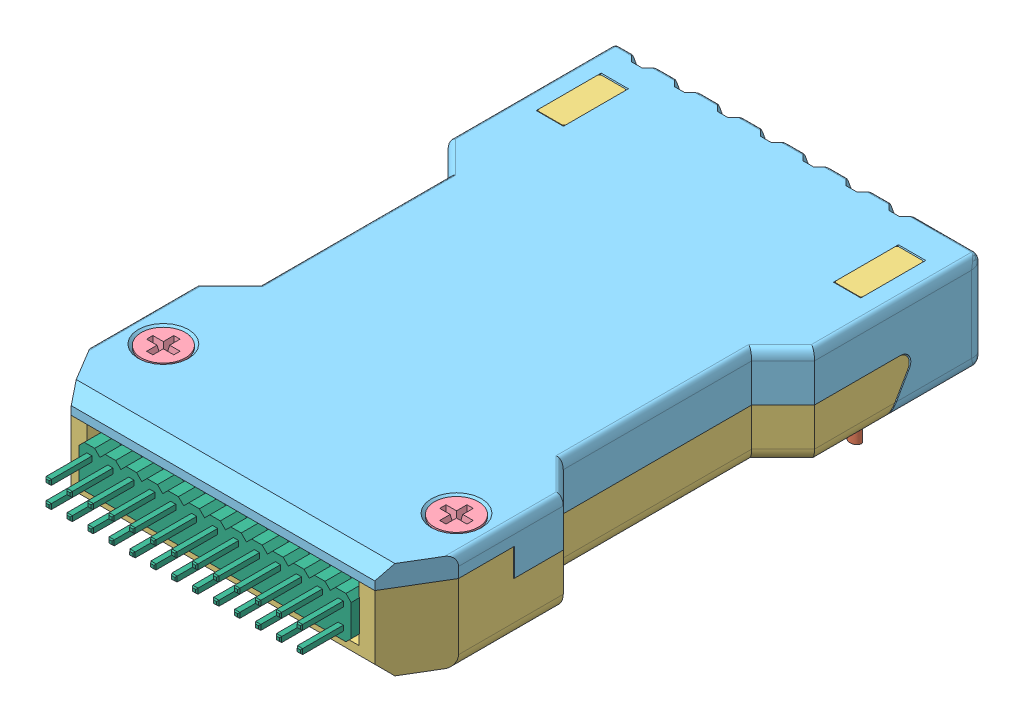
SolidWorks assembly connector2, configuration Default. Lengths in mm.
Overall size (35.01 15.03 59.91).
7 component instances, 6 part files, 16 mates.
Components (placement in the parent):
- board^connector2-1: board^connector2 [Default] at (-0.9944 1 -14.4999) x (0 0 1) z (-1 0 0) size (15 1.5 25.8) (virtual)
- RibbonCable-1: RibbonCable [Default] at (-0.9944 1 -17.6612) x (0 0 -1) z (1 0 0) size (35.03 12.57 25.33)
- EnclosureBody^connector2-1: EnclosureBody^connector2 [Default] at (-0.9944 -3.65 -28.6999) x (0 0 -1) z (1 0 0) size (51.47 9.3 35.01) (virtual)
- Self Tapping Cross recessed Screw 4Plastic^connector2-1: Self Tapping Cross recessed Screw 4Plastic^connector2 [Self Tap. Cross recessed Screw 2.6x10mm] at (-14.9944 5.55 -6.9999) x (0 -1 0) z (0 0 1) size (10 4.2 4.2) (virtual)
- Self Tapping Cross recessed Screw 4Plastic^connector2-2: Self Tapping Cross recessed Screw 4Plastic^connector2 [Self Tap. Cross recessed Screw 2.6x10mm] at (13.0056 5.55 -6.9999) x (0 -1 0) z (0 0 1) size (10 4.2 4.2) (virtual)
- Lid^connector2-1: Lid^connector2 [Default] at (-0.9944 3.65 -26.1999) x (0 0 -1) z (1 0 0) size (55.11 9.52 35.01) (virtual)
- PLD2-NN (DS-1025-05 - 2xNN) 2mm-1: PLD2-NN (DS-1025-05 - 2xNN) 2mm [DS-1025-05 - 2x13] at (11.0461 0.8366 2.1001) x (-1 0 0) z (0 0 -1) size (26 4 8.8)
Mates (geometry in assembly coordinates):
- Coincident4: coincident aligned: plane of EnclosureBody^cable-1 through (-18.4944 -1.65 1.3001) normal (0 0 1); plane of Lid^cable-1 through (-0.9944 5.65 1.3001) normal (0 0 1)
- Coincident5: coincident anti-aligned: plane of EnclosureBody^cable-1 through (-0.9944 3.65 -28.6999) normal (0 1 0); plane of Lid^cable-1 through (-0.9944 3.65 -26.1999) normal (0 -1 0)
- Concentric1: concentric anti-aligned: cylinder of Self Tapping Cross recessed Screw 4Plastic^cable-1 through (-14.9944 -4.45 -6.9999) axis (0 -1 0) radius 0.78; cylinder of Lid^cable-1 through (-14.9944 5.65 -6.9999) axis (0 1 0) radius 1.5
- Coincident7: coincident aligned: cone of Self Tapping Cross recessed Screw 4Plastic^cable-1 through (-14.9944 4.03 -6.9999) axis (0 -1 0); cone of Lid^cable-1 through (-14.9944 5.65 -6.9999) axis (0 -1 0)
- Concentric2: concentric anti-aligned: cylinder of Self Tapping Cross recessed Screw 4Plastic^cable-2 through (13.0056 -4.45 -6.9999) axis (0 -1 0) radius 0.78; cylinder of Lid^cable-1 through (13.0056 5.65 -6.9999) axis (0 1 0) radius 1.5
- Coincident8: coincident aligned: cone of Self Tapping Cross recessed Screw 4Plastic^cable-2 through (13.0056 4.03 -6.9999) axis (0 -1 0); cone of Lid^cable-1 through (13.0056 5.65 -6.9999) axis (0 -1 0)
- Coincident10: coincident aligned: plane of board^cable-1 through (-0.9944 1 -14.4999) normal (0 1 0); plane of RibbonCable^cable-1 through (-0.9944 1 -17.6612) normal (0 1 0)
- Coincident11: coincident anti-aligned: plane of board^cable-1 through (-0.9944 1 -14.4999) normal (0 1 0); plane of PBD-20-1 through (10.4356 1 0.5001) normal (0 -1 0)
- Coincident12: coincident anti-aligned: plane of board^cable-1 through (-13.8944 1.75 0.5001) normal (0 0 1); plane of PBD-20-1 through (9.1656 -1.54 0.5001) normal (0 0 -1)
- Coincident13: coincident anti-aligned: plane of EnclosureBody^cable-1 through (-0.9944 -3.65 -28.6999) normal (1 0 0); plane of PBD-20-1 through (-0.9944 -0.27 0.5001) normal (-1 0 0)
- Coincident14: coincident anti-aligned: plane of RibbonCable-1 through (-0.9944 1 -17.6612) normal (1 0 0); plane of PBD-20-1 through (-0.9944 -0.27 0.5001) normal (-1 0 0)
- Coincident15: coincident anti-aligned: plane of EnclosureBody^cable-1 through (-0.9944 1 -28.6999) normal (0 1 0); plane of PBD-20-1 through (10.4356 1 0.5001) normal (0 -1 0)
- Coincident16: coincident aligned: plane of board^cable-1 through (-0.9944 1 -14.4999) normal (-1 0 0); plane of PBD-20-1 through (-0.9944 -0.27 0.5001) normal (-1 0 0)
- Concentric3: concentric anti-aligned: cylinder of board^cable-1 through (13.0056 0.25 -6.9999) axis (0 1 0) radius 3.4; cylinder of EnclosureBody^cable-1 through (13.0056 3.65 -6.9999) axis (0 -1 0) radius 3.1
- Coincident17: coincident aligned: plane of EnclosureBody^cable-1 through (-0.9944 -3.65 -28.6999) normal (1 0 0); plane of Lid^cable-1 through (-0.9944 3.65 -26.1999) normal (1 0 0)
- Coincident18: coincident anti-aligned: plane of board^cable-1 through (-13.8944 1.75 0.5001) normal (0 0 1); plane of PLD2-NN (DS-1025-05 - 2xNN) 2mm-1 through (17.0461 2.1701 0.5001) normal (0 0 -1)
